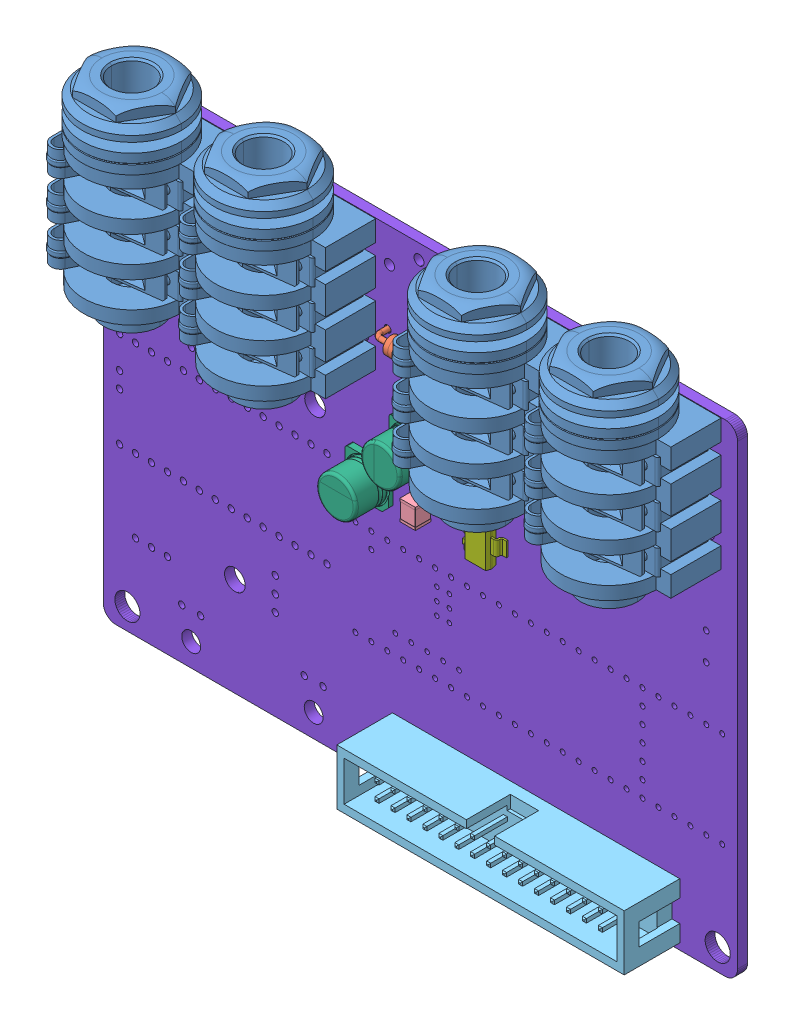
SolidWorks assembly teensy-dsp-pcb, configuration Default. Lengths in mm.
Overall size (101 84.91 19.7).
24 component instances, 8 part files, 0 mates.
Components (placement in the parent):
- teensy-dsp.step-1: teensy-dsp.step [Default] at origin size (101 84.91 19.7)
  - ACJS-IH--3DModel-STEP-56544.step-1: ACJS-IH--3DModel-STEP-56544.step [Default] at (168.5834 -75.1527 1.63) x (1 0 0) z (0 -1 0) size (20 19.7 33)
    - COMPOUND.step-1: AutoRecover Of COMPOUND.step.swar [Default] at origin size (20 19.7 33)
  - ACJS-IH--3DModel-STEP-56544.step-2: ACJS-IH--3DModel-STEP-56544.step [Default] at (189.5834 -75.1527 1.63) x (1 0 0) z (0 -1 0) size (20 19.7 33)
    - COMPOUND.step-1: AutoRecover Of COMPOUND.step.swar [Default] at origin size (20 19.7 33)
  - D_DO-41_SOD81_P10.16mm_Horizontal.step-1: D_DO-41_SOD81_P10.16mm_Horizontal.step [Default] at (146.4436 -79 1.63) size (10.96 2.72 5.71)
    - SOLID.step-1: SOLID.step [Default] at origin size (10.96 2.72 5.71)
  - R_1210_3225Metric.step-1: R_1210_3225Metric.step [Default] at (151.16 -85 1.63) size (3.2 2.5 0.55)
    - SOLID-0.step-1: SOLID-0.step [Default] at origin size (3.2 2.5 0.55)
  - C_1210_3225Metric.step-1: C_1210_3225Metric.step [Default] at (152.16 -100.4527 1.63) x (0 1 0) z (0 0 1) size (3.2 2.5 2.5)
    - SOLID-1.step-1: SOLID-1.step [Default] at origin size (3.2 2.5 2.5)
  - IDC-Header_2x15_P2.54mm_Vertical.step-1: AutoRecover Of IDC-Header_2x15_P2.54mm_Vertical.step.swar [Default] at (188.16 -134.4167 1.63) x (0 -1 0) z (0 0 1) size (9.1 45.76 12.1)
    - SOLID-2.step-1: SOLID-2.step [Default] at origin size (9.1 45.76 12.1)
  - CP_Elec_6.3x5.9.step-1: CP_Elec_6.3x5.9.step [Default] at (151.16 -92.6527 1.63) x (-1 0 0) z (0 0 1) size (8.61 8.6 5.9)
    - SOLID-3.step-1: SOLID-3.step [Default] at origin size (8.61 8.6 5.9)
  - SOT-223.step-1: SOT-223.step [Default] at (162.16 -99.6527 1.63) size (7 6.5 1.7)
    - SOLID-4.step-1: SOLID-4.step [Default] at origin size (7 6.5 1.7)
  - CP_Elec_6.3x5.9.step-2: CP_Elec_6.3x5.9.step [Default] at (144.16 -100.4527 1.63) x (0 1 0) z (0 0 1) size (8.61 8.6 5.9)
    - SOLID-3.step-1: SOLID-3.step [Default] at origin size (8.61 8.6 5.9)
  - ACJS-IH--3DModel-STEP-56544.step-3: ACJS-IH--3DModel-STEP-56544.step [Default] at (134.5834 -75.1527 1.63) x (1 0 0) z (0 -1 0) size (20 19.7 33)
    - COMPOUND.step-1: AutoRecover Of COMPOUND.step.swar [Default] at origin size (20 19.7 33)
  - ACJS-IH--3DModel-STEP-56544.step-4: ACJS-IH--3DModel-STEP-56544.step [Default] at (113.5834 -75.1527 1.63) x (1 0 0) z (0 -1 0) size (20 19.7 33)
    - COMPOUND.step-1: AutoRecover Of COMPOUND.step.swar [Default] at origin size (20 19.7 33)
  - PCB.step-1: AutoRecover Of PCB.step.swar [Default] at origin size (101 76.76 1.58)
